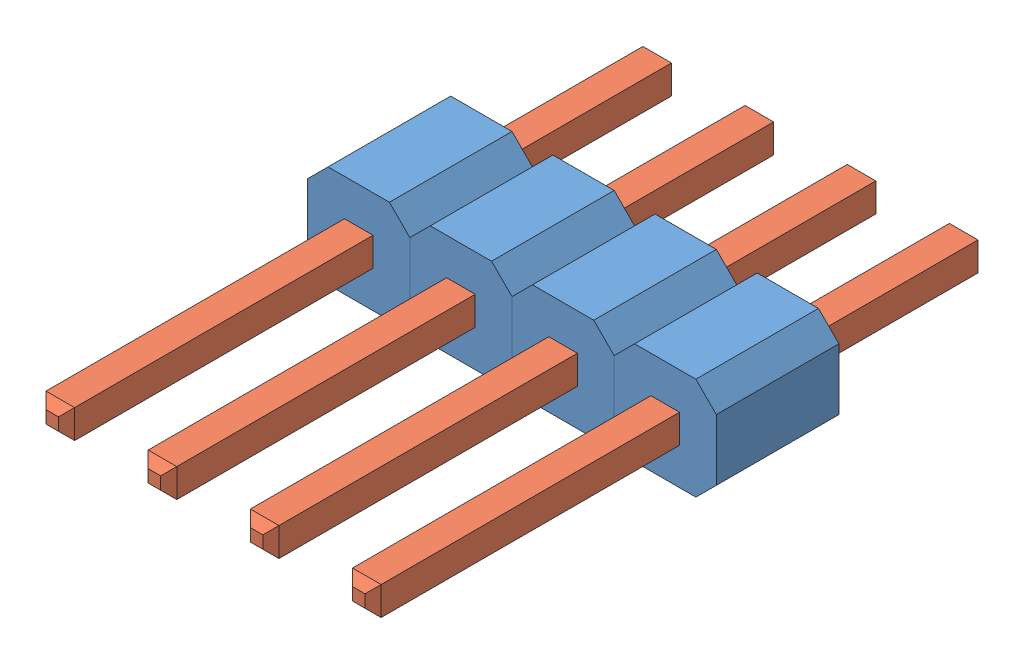
SolidWorks assembly Bloc 4 pins male, configuration Défaut. Lengths in mm.
Overall size (5.08 1.27 7.62).
8 component instances, 2 part files, 3 mates.
Components (placement in the parent):
- Pin_cmi2c_Base-1: Pin_cmi2c_Base [Défaut] at (-0.1729 -0.0306 1.524) size (1.27 1.27 1.52)
- Pin_cmi2c-1: Pin_cmi2c [Défaut] at (-0.1729 0.1472 -0.762) x (1 0 0) z (0 -1 0) size (0.36 7.62 0.36)
- Pin_cmi2c-2: Pin_cmi2c [Défaut] at (1.0971 0.1472 -0.762) x (1 0 0) z (0 -1 0) size (0.36 7.62 0.36)
- Pin_cmi2c-3: Pin_cmi2c [Défaut] at (2.3671 0.1472 -0.762) x (1 0 0) z (0 -1 0) size (0.36 7.62 0.36)
- Pin_cmi2c-4: Pin_cmi2c [Défaut] at (3.6371 0.1472 -0.762) x (1 0 0) z (0 -1 0) size (0.36 7.62 0.36)
- Pin_cmi2c_Base-2: Pin_cmi2c_Base [Défaut] at (1.0971 -0.0306 1.524) size (1.27 1.27 1.52)
- Pin_cmi2c_Base-3: Pin_cmi2c_Base [Défaut] at (2.3671 -0.0306 1.524) size (1.27 1.27 1.52)
- Pin_cmi2c_Base-4: Pin_cmi2c_Base [Défaut] at (3.6371 -0.0306 1.524) size (1.27 1.27 1.52)
Mates (geometry in assembly coordinates):
- Coïncidente1: coincident anti-aligned: plane of Pin_cmi2c_Base-1 through (-0.3507 0.1472 3.048) normal (0 -1 0); plane of Pin_cmi2c-1 through (-0.1729 0.1472 -0.762) normal (0 1 0)
- Coïncidente2: coincident anti-aligned: plane of Pin_cmi2c_Base-1 through (0.0049 0.1472 3.048) normal (-1 0 0); plane of Pin_cmi2c-1 through (0.0049 -0.2084 -0.762) normal (1 0 0)
- Distance1: distance = 3.81 mm aligned: plane of Pin_cmi2c_Base-1 through (-0.1729 -0.0306 3.048) normal (0 0 1); plane of Pin_cmi2c-1 through (-0.3507 -0.2084 6.858) normal (0 0 1)
